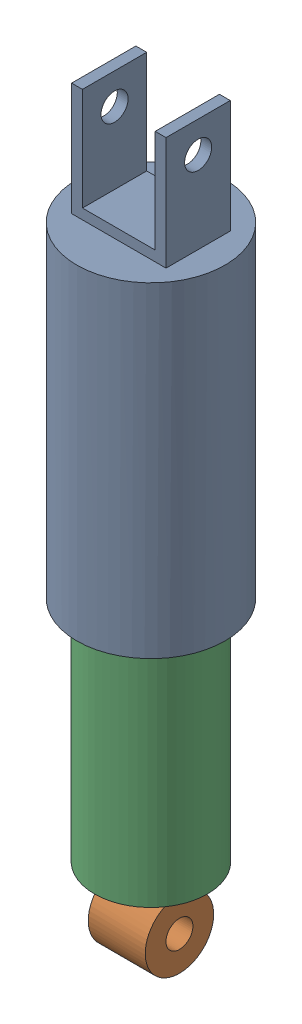
SolidWorks assembly Assembled, configuration Default. Lengths in mm.
Overall size (66.04 333.84 66.04).
2 component instances, 2 part files, 3 mates.
Components (placement in the parent):
- Forkedside-1: Forkedside [Default] at (-5.627 14.3157 -23.3968) size (66.04 195.41 66.04)
- RoundSide-1: RoundSide [Default] at (15.4042 -61.8843 -9.0839) x (0 0 1) z (0 -1 0) size (50.29 50.29 207.26)
Mates (geometry in assembly coordinates):
- Parallel1: parallel aligned: plane of Forkedside-1 through (36.4354 14.3157 5.229) normal (1 0 0); plane of RoundSide-1 through (28.1042 -253.9083 -9.0839) normal (1 0 0)
- Coincident1: coincident anti-aligned: circle of Forkedside-1; cylinder of RoundSide-1 through (15.4042 -130.7183 -9.0839) axis (0 1 0) radius 19.812
- LimitDistance1: limit distance = 38.1 mm anti-aligned: plane of Forkedside-1 through (15.4042 -23.7843 -9.0839) normal (0 -1 0); plane of RoundSide-1 through (15.4042 -61.8843 -9.0839) normal (0 1 0)
